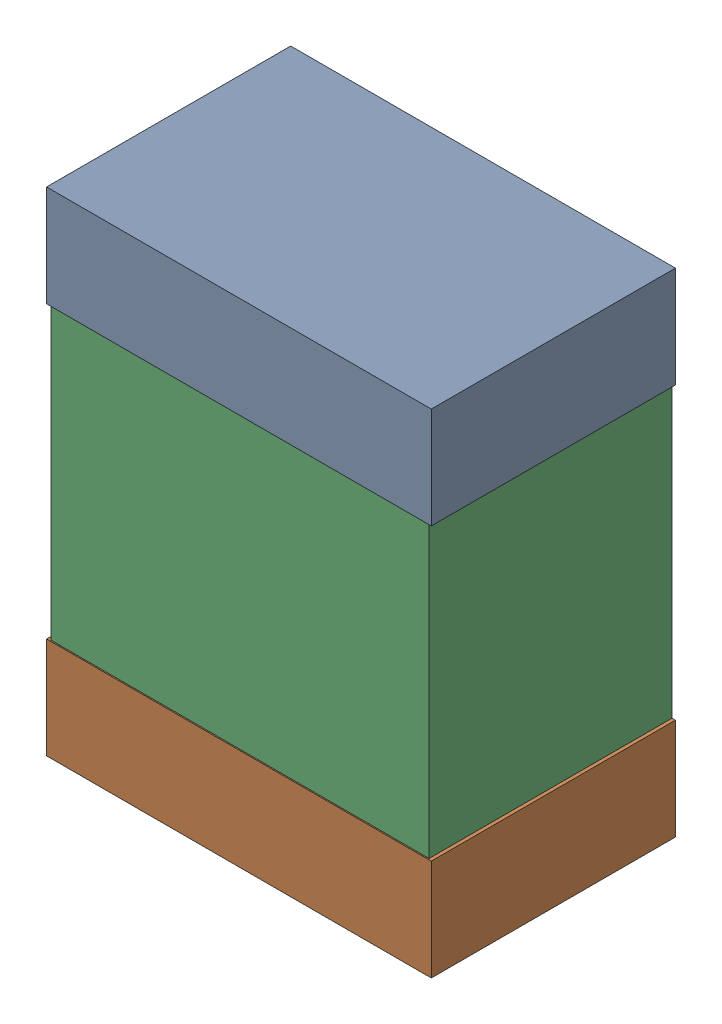
SolidWorks assembly C10Kanaloa_v2.0.0_Power, configuration Default. Lengths in mm.
Overall size (2.85 3.65 1.81).
6 component instances, 2 part files, 0 mates.
Components (placement in the parent):
- 334789552-1: 334789552 [Default] at (61.625 93.725 0) size (2.85 0.75 1.81)
  - Extruded_9-1: Extruded_9 [Default] at origin size (2.85 0.75 1.81)
- 334789552-2: 334789552 [Default] at (61.625 90.825 0) size (2.85 0.75 1.81)
  - Extruded_9-1: Extruded_9 [Default] at origin size (2.85 0.75 1.81)
- 334789424-1: 334789424 [Default] at (61.625 92.275 0) size (2.8 3.6 1.8)
  - Extruded_10-1: Extruded_10 [Default] at origin size (2.8 3.6 1.8)
